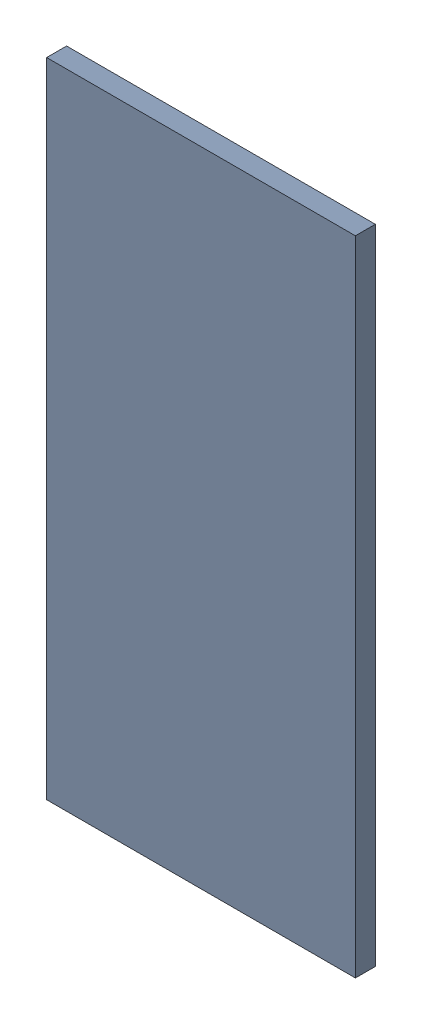
SolidWorks assembly Pad ADXL345-9(19.8mm,55.903mm) on Top Layer, configuration Predeterminado. Lengths in mm.
Overall size (0.55 1.15 0.04).
2 component instances, 1 part files, 0 mates.
Components (placement in the parent):
- Pad ADXL345-9(19.8mm,55.903mm) on Top Layer-1-1: Pad ADXL345-9(19.8mm,55.903mm) on Top Layer-1 [Predeterminado] at (-68.317 -44.187 -0.0457) size (0.55 1.15 0.04)
  - Pad ADXL345-9(19.8mm,55.903mm) on Top Layer-Part-1-1: Pad ADXL345-9(19.8mm,55.903mm) on Top Layer-Part-1 [Predeterminado] at origin size (0.55 1.15 0.04)
